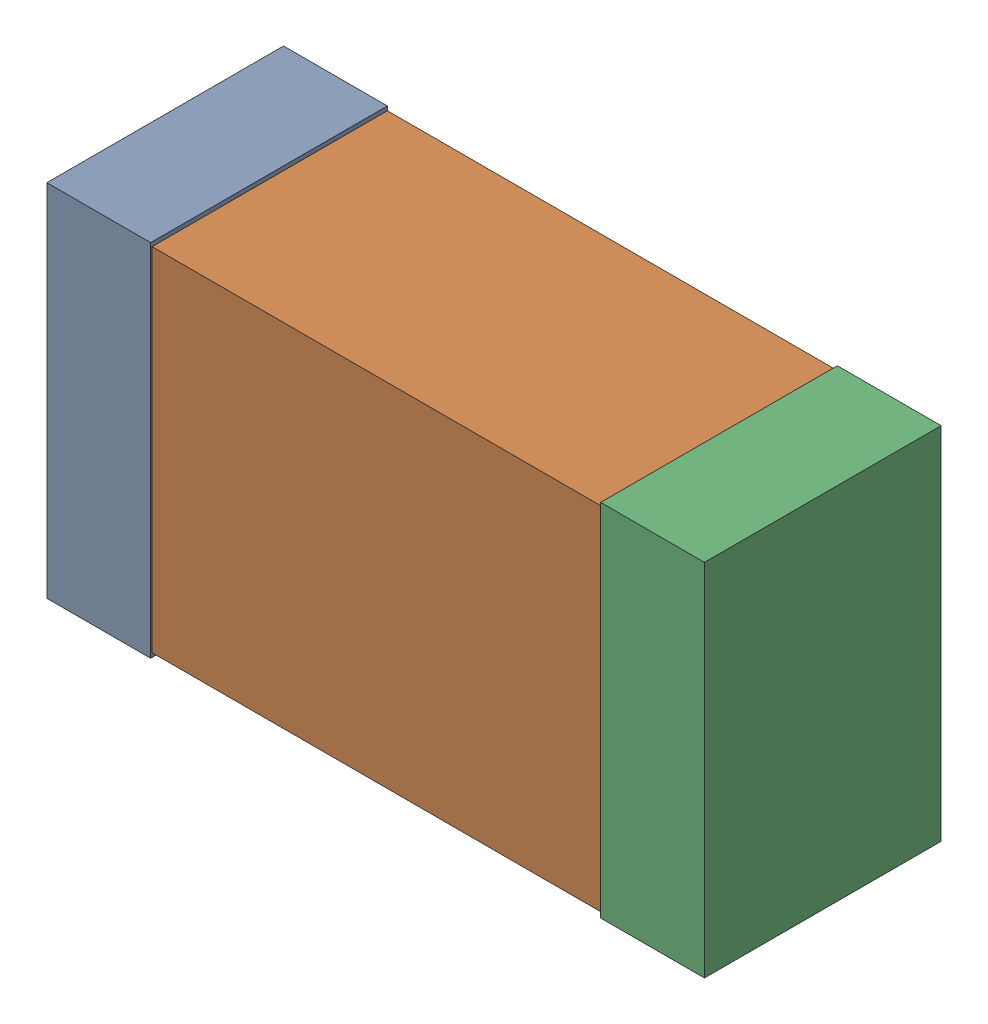
SolidWorks assembly C9_Motor_2Kanaloa_v2.0.0_Motor, configuration Default. Lengths in mm.
Overall size (2.38 1.3 0.85).
6 component instances, 2 part files, 0 mates.
Components (placement in the parent):
- 352877648-1: 352877648 [Default] at (119.289 50.292 0) size (0.38 1.3 0.85)
  - Extruded_14-1: Extruded_14 [Default] at origin size (0.38 1.3 0.85)
- 352877392-1: 352877392 [Default] at (120.289 50.292 0) size (2.2 1.27 0.85)
  - Extruded_15-1: Extruded_15 [Default] at origin size (2.2 1.27 0.85)
- 352877648-2: 352877648 [Default] at (121.289 50.292 0) size (0.38 1.3 0.85)
  - Extruded_14-1: Extruded_14 [Default] at origin size (0.38 1.3 0.85)
